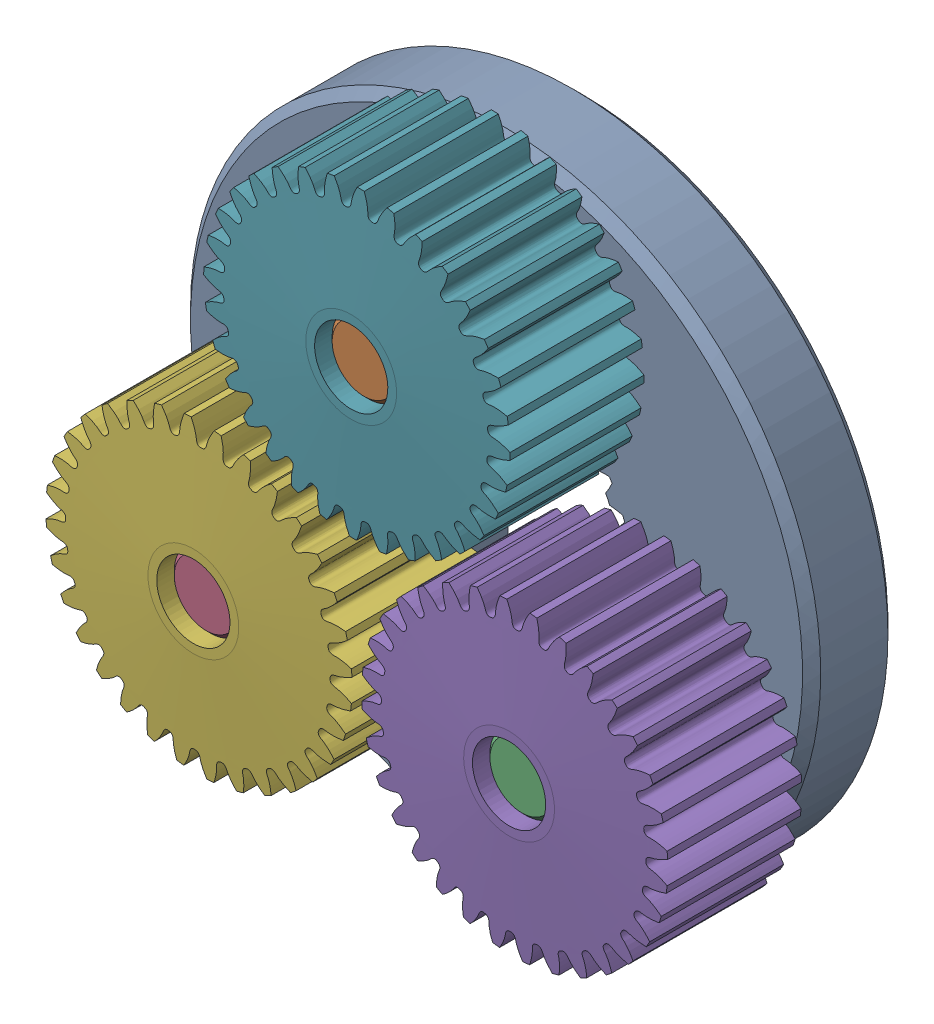
SolidWorks assembly 217-2625-100_1, configuration Default. Lengths in mm.
Overall size (39.26 38.9 12.7).
7 component instances, 3 part files, 0 mates.
Components (placement in the parent):
- 217-2625-008 Rev1_1-1: 217-2625-008 Rev1_1 [Default] at origin size (34.7 34.7 4.7)
- 217-2625-010 Rev1_1-1: 217-2625-010 Rev1_1 [Default] at (0 10.193 3.65) x (0.999813 0.019336 0) z (0 0 1) size (4 4 12)
- 217-2625-010 Rev1_1-2: 217-2625-010 Rev1_1 [Default] at (8.691 -5.3258 3.65) size (4 4 12)
- 217-2625-010 Rev1_1-3: 217-2625-010 Rev1_1 [Default] at (-8.691 -5.3258 3.65) size (4 4 12)
- 217-2625-005 Rev1_Planet_Revolving_Follower01_1-1: 217-2625-005 Rev1_Planet_Revolving_Follower01_1 [Default] at (8.691 -5.3258 6.35) x (0.932816 0.360354 0) z (0 0 1) size (16.91 16.92 8)
- 217-2625-005 Rev1_Planet_Revolving_Follower01_1-2: 217-2625-005 Rev1_Planet_Revolving_Follower01_1 [Default] at (-8.691 -5.3258 6.35) x (-0.932788 -0.360426 0) z (0 0 1) size (16.91 16.92 8)
- 217-2625-005 Rev1_Planet_Revolving_Follower01_1-3: 217-2625-005 Rev1_Planet_Revolving_Follower01_1 [Default] at (0 10.193 6.35) x (0.893583 0.448898 0) z (0 0 1) size (16.91 16.92 8)
